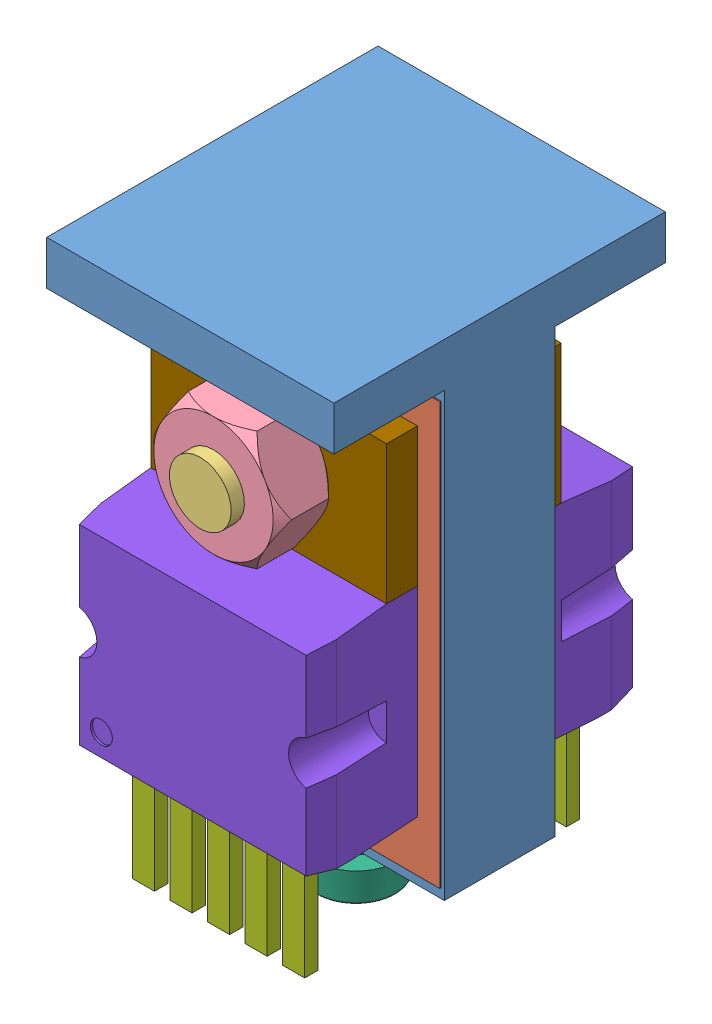
SolidWorks assembly HeatSinkAssembly, configuration Default. Lengths in mm.
Overall size (13 25.4 15).
24 component instances, 9 part files, 17 mates.
Components (placement in the parent):
- HeatSink-1: HeatSink [Default] at origin size (13 22 15)
- A15427-005-1: A15427-005 [Default] at (0 9.96 2.5) x (1 0 0) z (0 -1 0) size (12.7 0.05 19.08)
- A15427-005-2: A15427-005 [Default] at (0 9.96 -2.551) x (1 0 0) z (0 -1 0) size (12.7 0.05 19.08)
- M3x12-Plastic-1: M3x12-Plastic [Default] at (0 15 -3.951) x (1 0 0) z (0 1 0) size (5.5 13 5.5)
- M3-Nut-Plastic-2: M3-Nut-Plastic [Default] at (0 15 5.201) x (1 0 0) z (0 -1 0) size (6.86 2.5 5.4)
- parallel pin hardened_din-1: parallel pin hardened_din [DIN EN 28734 - 1 x 5 - A - St] at (5 4.0322 0) x (0 -1 0) z (0 0 1) size (5 1 1)
- parallel pin hardened_din-2: parallel pin hardened_din [DIN EN 28734 - 1 x 5 - A - St] at (-5 4.2 0) x (0 -1 0) z (0 0 1) size (5 1 1)
- slotted cheese head screw_din-1: slotted cheese head screw_din [DIN EN ISO 1207 - M2 x 5 - 5N] at (0 -3.4 0) x (0 1 0) z (-0.546944 0 0.837169) size (6.4 3.8 3.8)
- TO220-5-Standing-3: TO220-5-Standing [Default] at (0 0 -5.921) x (-1 0 0) z (0 0 -1) size (10.67 20.53 4.84)
  - P-1: P [Default] at (0 0.025 0) x (-1 0 0) z (0 -1 0) size (1 0.6 5)
  - P-6: P [Default] at (1.7 0.025 0) x (-1 0 0) z (0 -1 0) size (1 0.6 5)
  - P-7: P [Default] at (3.4 0.025 0) x (-1 0 0) z (0 -1 0) size (1 0.6 5)
  - P-8: P [Default] at (-1.7 0.025 0) x (-1 0 0) z (0 -1 0) size (1 0.6 5)
  - P-9: P [Default] at (-3.4 0.025 0) x (-1 0 0) z (0 -1 0) size (1 0.6 5)
  - Body-2: Body [Default] at (0 7.15 -3.36) x (1 0 0) z (0 -1 0) size (10.67 4.83 9.25)
  - EP-2: EP [Default] at (0 15 -3.37) x (1 0 0) z (0 -1 0) size (10.67 1.4 12.88)
- TO220-5-Standing-4: TO220-5-Standing [Default] at (0 0 5.921) size (10.67 20.53 4.84)
  - P-1: P [Default] at (0 0.025 0) x (-1 0 0) z (0 -1 0) size (1 0.6 5)
  - P-6: P [Default] at (1.7 0.025 0) x (-1 0 0) z (0 -1 0) size (1 0.6 5)
  - P-7: P [Default] at (3.4 0.025 0) x (-1 0 0) z (0 -1 0) size (1 0.6 5)
  - P-8: P [Default] at (-1.7 0.025 0) x (-1 0 0) z (0 -1 0) size (1 0.6 5)
  - P-9: P [Default] at (-3.4 0.025 0) x (-1 0 0) z (0 -1 0) size (1 0.6 5)
  - Body-2: Body [Default] at (0 7.15 -3.36) x (1 0 0) z (0 -1 0) size (10.67 4.83 9.25)
  - EP-2: EP [Default] at (0 15 -3.37) x (1 0 0) z (0 -1 0) size (10.67 1.4 12.88)
Mates (geometry in assembly coordinates):
- Coincident1: coincident: plane of HeatSink-1 through (-6.5 20 2.5) normal (0 0 1); plane of A15427-005-1 through (0 9.96 2.5) normal (0 0 -1)
- Concentric1: concentric: cylinder of HeatSink-1 through (0 15 2.5) axis (0 0 1) radius 1.5; cylinder of A15427-005-1 through (0 15 2.5) axis (0 0 1) radius 1.5818
- Parallel1: parallel: plane of A15427-005-1 through (-6.35 0.42 2.551) normal (0 -1 0); plane of assembly through (0 0 0) normal (0 1 0)
- Coincident3: coincident: plane of HeatSink-1 through (-6.5 20 -2.5) normal (0 0 -1); plane of A15427-005-2 through (0 9.96 -2.5) normal (0 0 1)
- Concentric2: concentric: cylinder of HeatSink-1 through (0 15 2.5) axis (0 0 1) radius 1.5; cylinder of A15427-005-2 through (0 15 -2.551) axis (0 0 1) radius 1.5818
- Parallel2: parallel: plane of A15427-005-2 through (-6.35 0.42 -2.5) normal (0 -1 0); plane of assembly through (0 0 0) normal (0 1 0)
- Concentric5: concentric: cylinder of HeatSink-1 through (0 15 2.5) axis (0 0 1) radius 1.5; cylinder of M3x12-Plastic-1 through (0 15 7.049) axis (0 0 -1) radius 1.4
- Concentric7: concentric: cylinder of M3x12-Plastic-1 through (0 15 7.049) axis (0 0 -1) radius 1.4; cylinder of M3-Nut-Plastic-2 through (0 15 6.451) axis (0 0 1) radius 1.25
- Concentric8: concentric: cylinder of HeatSink-1 through (-5 0 0) axis (0 -1 0) radius 0.5; cylinder of parallel pin hardened_din-2 through (-5 10.55 0) axis (0 1 0) radius 0.5
- Concentric9: concentric: cylinder of HeatSink-1 through (5 0 0) axis (0 -1 0) radius 0.5; cylinder of parallel pin hardened_din-1 through (5 10.3822 0) axis (0 1 0) radius 0.5
- Coincident11: coincident: cone of HeatSink-1 through (5 4 0) axis (0 1 0); circle of parallel pin hardened_din-1
- Coincident12: coincident: cone of HeatSink-1 through (-5 4 0) axis (0 1 0); circle of parallel pin hardened_din-2
- Concentric10: concentric: cylinder of HeatSink-1 through (0 0 0) axis (0 -1 0) radius 0.8; cylinder of slotted cheese head screw_din-1 through (0 -28.8 0) axis (0 -1 0) radius 1
- Distance1: distance = 2 mm: plane of slotted cheese head screw_din-1 through (-0.8372 -2 -0.5469) normal (0 1 0); plane of HeatSink-1 through (0 0 0) normal (0 -1 0)
- Coincident14: coincident: plane of A15427-005-2 through (0 9.96 -2.551) normal (0 0 -1); plane of TO220-5-Standing-3/EP-2 through (0 15 -2.551) normal (0 0 1)
- Concentric11: concentric: cylinder of HeatSink-1 through (0 15 2.5) axis (0 0 1) radius 1.5; cylinder of TO220-5-Standing-3/EP-2 through (0 15 -3.951) axis (0 0 1) radius 1.855
- Parallel5: parallel: plane of HeatSink-1 through (0 0 0) normal (0 -1 0); plane of TO220-5-Standing-3/Body-2 through (5.335 2.525 -7.391) normal (0 -1 0)
